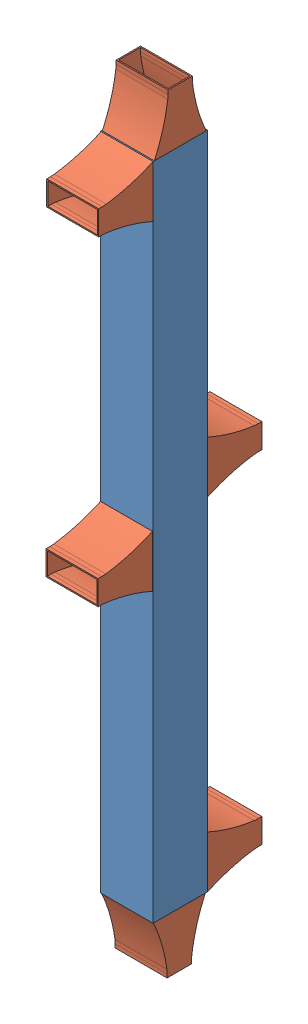
SolidWorks assembly Heat Exchange Assembly, configuration Default. Lengths in mm.
Overall size (85.97 1257.6 267).
7 component instances, 2 part files, 15 mates.
Components (placement in the parent):
- Heat Exchanger (1)-1: Heat Exchanger (1) [Default] at (299.8905 39.0568 794.6218) size (85.97 1079.6 89)
- Manifold-1: Manifold [Default] at (299.8905 39.0568 794.6218) x (-1 0 0) z (0 0 1) size (85 89 103.94)
- Manifold-2: Manifold [Default] at (299.8905 1118.6568 793.1218) size (85 89 103.94)
- Manifold-3: Manifold [Default] at (299.8905 1076.1568 837.6218) x (1 0 0) z (0 -1 0) size (85 89 103.94)
- Manifold-4: Manifold [Default] at (298.9205 551.5568 837.6218) x (1 0 0) z (0 -1 0) size (85 89 103.94)
- Manifold-5: Manifold [Default] at (299.8905 81.5568 748.6218) x (1 0 0) z (0 1 0) size (85 89 103.94)
- Manifold-6: Manifold [Default] at (299.8905 641.133 748.6218) x (1 0 0) z (0 1 0) size (85 89 103.94)
Mates (geometry in assembly coordinates):
- Coincident6: coincident: plane of Heat Exchanger (1)-1 through (257.3905 1118.6568 748.6218) normal (0 0 -1); plane of Manifold-5 through (299.8905 81.5568 748.6218) normal (0 0 1)
- Coincident7: coincident: plane of Heat Exchanger (1)-1 through (342.3905 1118.6568 748.6218) normal (1 0 0); plane of Manifold-5 through (342.3905 124.0568 748.6218) normal (1 0 0)
- Coincident8: coincident aligned: line of Heat Exchanger (1)-1 through (342.3905 39.0568 748.6218) axis (-1 0 0); line of Manifold-5 through (342.3905 39.0568 748.6218) axis (-1 0 0)
- Coincident9: coincident: plane of Heat Exchanger (1)-1 through (299.8905 1118.6568 794.6218) normal (0 1 0); plane of Manifold-2 through (299.8905 1118.6568 793.1218) normal (0 -1 0)
- Coincident10: coincident: plane of Heat Exchanger (1)-1 through (342.3905 1118.6568 748.6218) normal (1 0 0); plane of Manifold-2 through (342.3905 1118.6568 835.6218) normal (1 0 0)
- Distance1: distance = 2 mm: line of Manifold-2 through (257.3905 1118.6568 835.6218) axis (1 0 0); plane of Heat Exchanger (1)-1 through (342.3905 1118.6568 837.6218) normal (0 0 1)
- Coincident12: coincident: plane of Heat Exchanger (1)-1 through (342.3905 1118.6568 837.6218) normal (0 0 1); plane of Manifold-3 through (299.8905 1076.1568 837.6218) normal (0 0 -1)
- Coincident13: coincident: plane of Heat Exchanger (1)-1 through (342.3905 1118.6568 748.6218) normal (1 0 0); plane of Manifold-3 through (342.3905 1033.6568 837.6218) normal (1 0 0)
- Coincident14: coincident anti-aligned: line of Heat Exchanger (1)-1 through (256.4205 1118.6568 837.6218) axis (1 0 0); line of Manifold-3 through (342.3905 1118.6568 837.6218) axis (-1 0 0)
- Coincident15: coincident: plane of Heat Exchanger (1)-1 through (257.3905 1118.6568 748.6218) normal (0 0 -1); plane of Manifold-6 through (299.8905 641.133 748.6218) normal (0 0 1)
- Coincident16: coincident: plane of Heat Exchanger (1)-1 through (342.3905 1118.6568 748.6218) normal (1 0 0); plane of Manifold-6 through (342.3905 683.633 748.6218) normal (1 0 0)
- Distance2: distance = 435.0238 mm: line of Manifold-6 through (257.3905 683.633 748.6218) axis (1 0 0); line of Heat Exchanger (1)-1 through (342.3905 1118.6568 748.6218) axis (-1 0 0)
- Coincident18: coincident: plane of Heat Exchanger (1)-1 through (342.3905 1118.6568 837.6218) normal (0 0 1); plane of Manifold-4 through (298.9205 551.5568 837.6218) normal (0 0 -1)
- Coincident19: coincident: plane of Heat Exchanger (1)-1 through (256.4205 1118.6568 837.6218) normal (-1 0 0); plane of Manifold-4 through (256.4205 594.0568 837.6218) normal (-1 0 0)
- Distance3: distance = 470 mm: line of Heat Exchanger (1)-1 through (256.4205 39.0568 837.6218) axis (1 0 0); line of Manifold-4 through (256.4205 509.0568 837.6218) axis (1 0 0)
